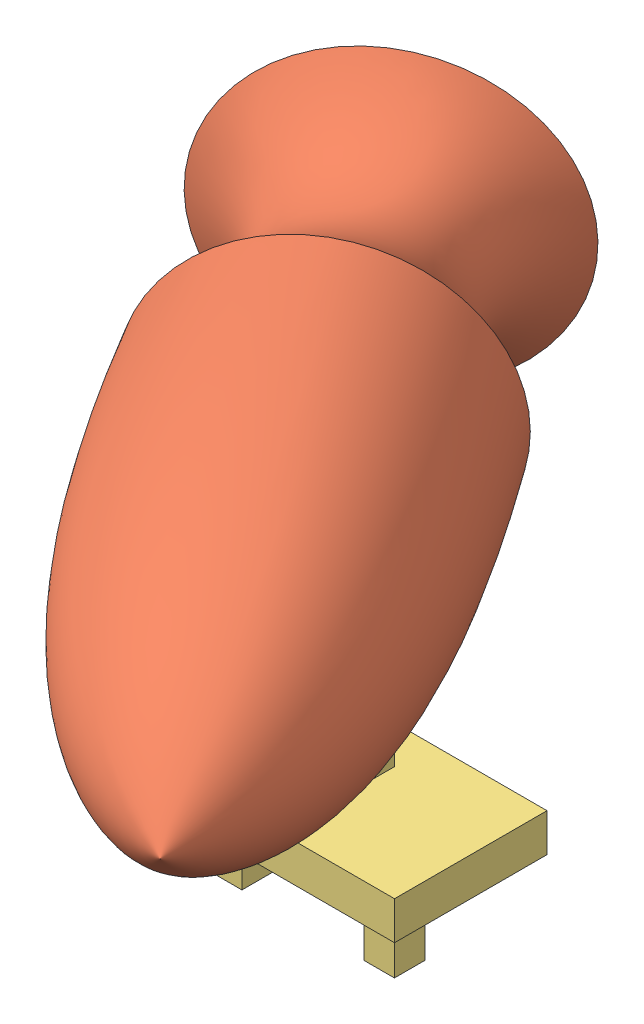
SolidWorks assembly rocket final, configuration Default. Lengths in mm.
Overall size (5147.89 4331.7 5752.13).
4 component instances, 3 part files, 2 mates.
Components (placement in the parent):
- rocket body final-1: rocket body final [Default] at (-7.8687 2130.5874 1542.4415) x (0.683806 -0.562831 -0.464361) z (-0.538646 0.039925 -0.841586) size (2076.69 2101.98 5000)
  - rocket part-1: rocket part [Default] at (864.0757 1233.5365 -591.098) x (-0.002316 0.049877 0.998753) z (0.826569 -0.562036 0.029984) size (300 200 300)
  - Xdesign rocket body-1: Xdesign rocket body [Default] at (201.5517 261.6908 27.8048) size (2076.69 2076.69 5000)
- Xdesign rocket plate-1: Xdesign rocket plate [Default] at (294.2239 -447.7576 1978.9475) size (2000 1650 1000)
Mates (geometry in assembly coordinates):
- Coincident3: coincident anti-aligned: plane of rocket body final-1/rocket part-1 through (294.2239 602.2424 1978.9475) normal (0 -1 0); plane of Xdesign rocket plate-1 through (294.2239 602.2424 1978.9475) normal (0 1 0)
- Coincident4: coincident aligned: circle of rocket body final-1/rocket part-1; circle of Xdesign rocket plate-1
